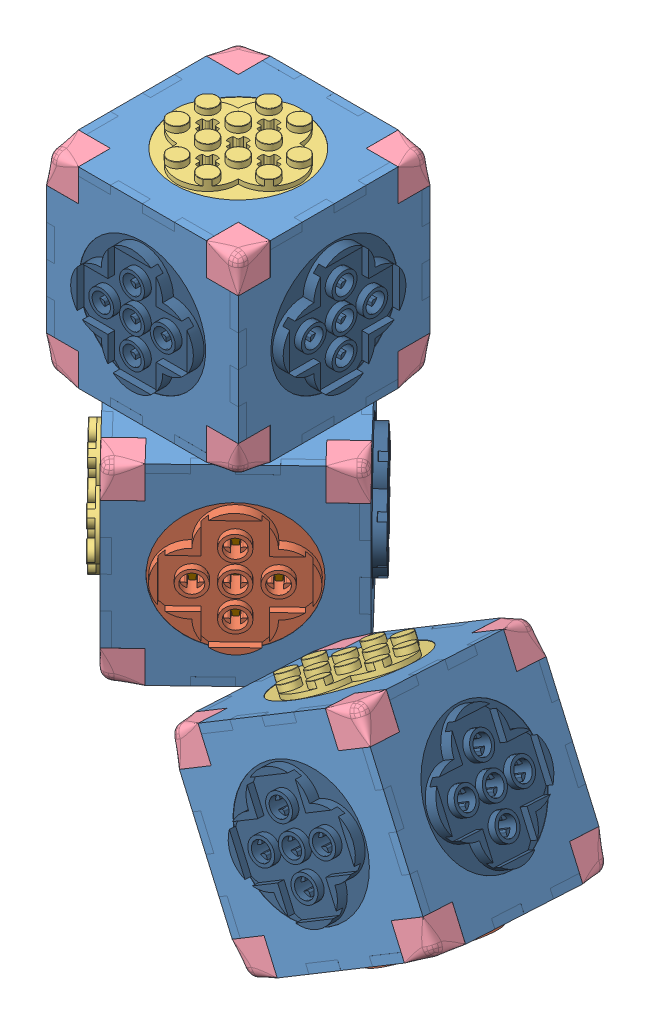
SolidWorks assembly demo, configuration Default. Lengths in mm.
Overall size (276.34 303.89 216.73).
87 component instances, 10 part files, 2 mates.
Components (placement in the parent):
- Assem2.2-1: Assem2.2 [Default] at (21.6339 91.8261 157.3479) size (152.36 197.99 106.71)
  - Partfina1.1-1: Partfina1.1 [Default] at (20.7363 27.7701 41.1813) size (50 50 2.1) (hidden)
  - Partfina1.1-2: Partfina1.1 [Default] at (38.638 27.7701 13.2813) x (0.000056 0 -1) z (1 0 0.000056) size (50 50 2.1) (hidden)
  - Partfina1.1-4: Partfina1.1 [Default] at (10.7387 27.7728 -4.62) x (-1 0.00009 -0.000071) z (0.000071 -0.000198 -1) size (50 50 2.1)
  - Partfina1.1-5: Partfina1.1 [Default] at (-7.1609 27.774 23.278) x (0 0 1) z (-1 0 0) size (50 50 2.1)
  - Partfina1.1-6: Partfina1.1 [Default] at (20.7363 -0.1265 13.2846) x (0 0 -1) z (0 -1 0) size (50 50 2.1)
  - 42_NEGATIVE_TURNok-1: 42_NEGATIVE_TURNok [Default] at (15.7363 -4.9265 26.2846) x (1 0 0.000001) z (-0.000001 0 1) size (117.99 40.06 72.36)
  - Partfina1.1-7: Partfina1.1 [Default] at (10.7391 45.674 23.278) x (-1 0 0) z (0 1 0) size (50 50 2.1)
  - 42_positive-1: 42_positive [Default] at (118.3117 45.674 32.2842) size (63.9 8.98 46.69)
  - 42_positive-2: 42_positive [Default] at (-7.1609 36.7803 -84.2945) x (0 0 -1) z (0 1 0) size (63.9 8.98 46.69)
  - 42_positive-3: 42_positive [Default] at (1.7335 125.3451 -4.64) x (0.000015 1 -0.000198) z (-1 0.000015 -0.000071) size (63.9 8.98 46.69)
  - angle-1: angle [Default] at (-5.0959 39.444 -2.5536) size (10.84 10.84 10.84)
  - angle-2: angle [Default] at (36.5739 39.4401 -2.5505) x (-0.000056 0 1) z (-1 0 -0.000056) size (10.84 10.84 10.84)
  - angle-3: angle [Default] at (36.568 39.4401 39.1163) x (-1 0 0) z (0 0 -1) size (10.84 10.84 10.84)
  - angle-4: angle [Default] at (-5.0959 39.444 39.1097) x (0 0 -1) z (1 0 0) size (10.84 10.84 10.84)
  - angle-5: angle [Default] at (36.568 6.1035 39.1163) x (0 0 -1) z (-1 0 0) size (10.84 10.84 10.84)
  - angle-6: angle [Default] at (36.5739 6.1035 -2.5505) x (-1 0 -0.000056) z (-0.000056 0 1) size (10.84 10.84 10.84)
  - angle-7: angle [Default] at (-5.0951 6.108 -2.5519) x (-0.000071 0.000198 1) z (1 -0.00009 0.000071) size (10.84 10.84 10.84)
  - angle-8: angle [Default] at (-5.0959 6.1074 39.1097) x (1 0 0) z (0 0 -1) size (10.84 10.84 10.84)
  - HS-55_Servo-2: HS-55_Servo [Default] at (15.7363 4.1163 18.2846) x (0.707107 0 -0.707106) z (-0.707106 0 -0.707107) size (32.54 27 11.73)
    - Hi-Tec_HS-55_Body-1: Hi-Tec_HS-55_Body [Default] at origin size (32.54 24.06 11.73)
    - Hi-Tec_HS-55_Shaft-1: Hi-Tec_HS-55_Shaft [Default] at (0 3 0) x (0.999553 0 0.029907) z (-0.029907 0 0.999553) size (3.75 3 3.75)
  - motor_laser adapter-1: motor_laser adapter [Default] at (19.7166 -9.2257 25.7533) x (0.707107 0 -0.707107) z (-0.707107 0 -0.707107) size (56.91 27 56.91)
  - motor_fit-1: motor_fit [Default] at (19.7166 -9.7157 25.7533) x (0.707107 0 -0.707106) z (-0.707106 0 -0.707107) size (32.54 27 22)
  - 42_NEGATIVE_TURN-3: 42_NEGATIVE_TURN [Default] at (15.7363 -1.4265 26.2846) size (115.49 39.26 69.86)
  - 42_NEGATIVE-1: 42_NEGATIVE [Default] at (43.4391 22.774 10.278) x (0 -1 0) z (0 0 -1) size (117.99 40.06 72.36)
  - Partfina1.1-8: Partfina1.1 [Default] at (38.6391 27.774 13.278) x (0 0 -1) z (1 0 0) size (50 50 2.1)
  - Partfina1.1-9: Partfina1.1 [Default] at (20.7391 27.774 41.178) size (50 50 2.1)
  - 42_NEGATIVE-2: 42_NEGATIVE [Default] at (7.7391 22.774 45.978) x (0 1 0) z (-1 0 0) size (117.99 40.06 72.36)
- Assem2.2-2: Assem2.2 [Default] at (39.9561 76.5387 204.7196) x (0 -1 0) z (0.721396 0 -0.692523) size (152.36 197.99 106.71)
  - Partfina1.1-1: Partfina1.1 [Default] at (20.7363 27.7701 41.1813) size (50 50 2.1) (hidden)
  - Partfina1.1-2: Partfina1.1 [Default] at (38.638 27.7701 13.2813) x (0.000056 0 -1) z (1 0 0.000056) size (50 50 2.1) (hidden)
  - Partfina1.1-4: Partfina1.1 [Default] at (10.7387 27.7728 -4.62) x (-1 0.00009 -0.000071) z (0.000071 -0.000198 -1) size (50 50 2.1)
  - Partfina1.1-5: Partfina1.1 [Default] at (-7.1609 27.774 23.278) x (0 0 1) z (-1 0 0) size (50 50 2.1)
  - Partfina1.1-6: Partfina1.1 [Default] at (20.7363 -0.1265 13.2846) x (0 0 -1) z (0 -1 0) size (50 50 2.1)
  - 42_NEGATIVE_TURNok-1: 42_NEGATIVE_TURNok [Default] at (15.7363 -4.9265 26.2846) x (1 0 0.000001) z (-0.000001 0 1) size (117.99 40.06 72.36)
  - Partfina1.1-7: Partfina1.1 [Default] at (10.7391 45.674 23.278) x (-1 0 0) z (0 1 0) size (50 50 2.1)
  - 42_positive-1: 42_positive [Default] at (118.3117 45.674 32.2842) size (63.9 8.98 46.69)
  - 42_positive-2: 42_positive [Default] at (-7.1609 36.7803 -84.2945) x (0 0 -1) z (0 1 0) size (63.9 8.98 46.69)
  - 42_positive-3: 42_positive [Default] at (1.7335 125.3451 -4.64) x (0.000015 1 -0.000198) z (-1 0.000015 -0.000071) size (63.9 8.98 46.69)
  - angle-1: angle [Default] at (-5.0959 39.444 -2.5536) size (10.84 10.84 10.84)
  - angle-2: angle [Default] at (36.5739 39.4401 -2.5505) x (-0.000056 0 1) z (-1 0 -0.000056) size (10.84 10.84 10.84)
  - angle-3: angle [Default] at (36.568 39.4401 39.1163) x (-1 0 0) z (0 0 -1) size (10.84 10.84 10.84)
  - angle-4: angle [Default] at (-5.0959 39.444 39.1097) x (0 0 -1) z (1 0 0) size (10.84 10.84 10.84)
  - angle-5: angle [Default] at (36.568 6.1035 39.1163) x (0 0 -1) z (-1 0 0) size (10.84 10.84 10.84)
  - angle-6: angle [Default] at (36.5739 6.1035 -2.5505) x (-1 0 -0.000056) z (-0.000056 0 1) size (10.84 10.84 10.84)
  - angle-7: angle [Default] at (-5.0951 6.108 -2.5519) x (-0.000071 0.000198 1) z (1 -0.00009 0.000071) size (10.84 10.84 10.84)
  - angle-8: angle [Default] at (-5.0959 6.1074 39.1097) x (1 0 0) z (0 0 -1) size (10.84 10.84 10.84)
  - HS-55_Servo-2: HS-55_Servo [Default] at (15.7363 4.1163 18.2846) x (0.707107 0 -0.707106) z (-0.707106 0 -0.707107) size (32.54 27 11.73)
    - Hi-Tec_HS-55_Body-1: Hi-Tec_HS-55_Body [Default] at origin size (32.54 24.06 11.73)
    - Hi-Tec_HS-55_Shaft-1: Hi-Tec_HS-55_Shaft [Default] at (0 3 0) x (0.999553 0 0.029907) z (-0.029907 0 0.999553) size (3.75 3 3.75)
  - motor_laser adapter-1: motor_laser adapter [Default] at (19.7166 -9.2257 25.7533) x (0.707107 0 -0.707107) z (-0.707107 0 -0.707107) size (56.91 27 56.91)
  - motor_fit-1: motor_fit [Default] at (19.7166 -9.7157 25.7533) x (0.707107 0 -0.707106) z (-0.707106 0 -0.707107) size (32.54 27 22)
  - 42_NEGATIVE_TURN-3: 42_NEGATIVE_TURN [Default] at (15.7363 -1.4265 26.2846) size (115.49 39.26 69.86)
  - 42_NEGATIVE-1: 42_NEGATIVE [Default] at (43.4391 22.774 10.278) x (0 -1 0) z (0 0 -1) size (117.99 40.06 72.36)
  - Partfina1.1-8: Partfina1.1 [Default] at (38.6391 27.774 13.278) x (0 0 -1) z (1 0 0) size (50 50 2.1)
  - Partfina1.1-9: Partfina1.1 [Default] at (20.7391 27.774 41.178) size (50 50 2.1)
  - 42_NEGATIVE-2: 42_NEGATIVE [Default] at (7.7391 22.774 45.978) x (0 1 0) z (-1 0 0) size (117.99 40.06 72.36)
- Assem2.2-3: Assem2.2 [Default] at (104.2409 14.6081 192.6606) x (0.87122 0.475159 -0.123287) z (0.072918 0.123097 0.989712) size (152.36 197.99 106.71)
  - Partfina1.1-1: Partfina1.1 [Default] at (20.7363 27.7701 41.1813) size (50 50 2.1) (hidden)
  - Partfina1.1-2: Partfina1.1 [Default] at (38.638 27.7701 13.2813) x (0.000056 0 -1) z (1 0 0.000056) size (50 50 2.1) (hidden)
  - Partfina1.1-4: Partfina1.1 [Default] at (10.7387 27.7728 -4.62) x (-1 0.00009 -0.000071) z (0.000071 -0.000198 -1) size (50 50 2.1)
  - Partfina1.1-5: Partfina1.1 [Default] at (-7.1609 27.774 23.278) x (0 0 1) z (-1 0 0) size (50 50 2.1)
  - Partfina1.1-6: Partfina1.1 [Default] at (20.7363 -0.1265 13.2846) x (0 0 -1) z (0 -1 0) size (50 50 2.1)
  - 42_NEGATIVE_TURNok-1: 42_NEGATIVE_TURNok [Default] at (15.7363 -4.9265 26.2846) x (1 0 0.000001) z (-0.000001 0 1) size (117.99 40.06 72.36)
  - Partfina1.1-7: Partfina1.1 [Default] at (10.7391 45.674 23.278) x (-1 0 0) z (0 1 0) size (50 50 2.1)
  - 42_positive-1: 42_positive [Default] at (118.3117 45.674 32.2842) size (63.9 8.98 46.69)
  - 42_positive-2: 42_positive [Default] at (-7.1609 36.7803 -84.2945) x (0 0 -1) z (0 1 0) size (63.9 8.98 46.69)
  - 42_positive-3: 42_positive [Default] at (1.7335 125.3451 -4.64) x (0.000015 1 -0.000198) z (-1 0.000015 -0.000071) size (63.9 8.98 46.69)
  - angle-1: angle [Default] at (-5.0959 39.444 -2.5536) size (10.84 10.84 10.84)
  - angle-2: angle [Default] at (36.5739 39.4401 -2.5505) x (-0.000056 0 1) z (-1 0 -0.000056) size (10.84 10.84 10.84)
  - angle-3: angle [Default] at (36.568 39.4401 39.1163) x (-1 0 0) z (0 0 -1) size (10.84 10.84 10.84)
  - angle-4: angle [Default] at (-5.0959 39.444 39.1097) x (0 0 -1) z (1 0 0) size (10.84 10.84 10.84)
  - angle-5: angle [Default] at (36.568 6.1035 39.1163) x (0 0 -1) z (-1 0 0) size (10.84 10.84 10.84)
  - angle-6: angle [Default] at (36.5739 6.1035 -2.5505) x (-1 0 -0.000056) z (-0.000056 0 1) size (10.84 10.84 10.84)
  - angle-7: angle [Default] at (-5.0951 6.108 -2.5519) x (-0.000071 0.000198 1) z (1 -0.00009 0.000071) size (10.84 10.84 10.84)
  - angle-8: angle [Default] at (-5.0959 6.1074 39.1097) x (1 0 0) z (0 0 -1) size (10.84 10.84 10.84)
  - HS-55_Servo-2: HS-55_Servo [Default] at (15.7363 4.1163 18.2846) x (0.707107 0 -0.707106) z (-0.707106 0 -0.707107) size (32.54 27 11.73)
    - Hi-Tec_HS-55_Body-1: Hi-Tec_HS-55_Body [Default] at origin size (32.54 24.06 11.73)
    - Hi-Tec_HS-55_Shaft-1: Hi-Tec_HS-55_Shaft [Default] at (0 3 0) x (0.999553 0 0.029907) z (-0.029907 0 0.999553) size (3.75 3 3.75)
  - motor_laser adapter-1: motor_laser adapter [Default] at (19.7166 -9.2257 25.7533) x (0.707107 0 -0.707107) z (-0.707107 0 -0.707107) size (56.91 27 56.91)
  - motor_fit-1: motor_fit [Default] at (19.7166 -9.7157 25.7533) x (0.707107 0 -0.707106) z (-0.707106 0 -0.707107) size (32.54 27 22)
  - 42_NEGATIVE_TURN-3: 42_NEGATIVE_TURN [Default] at (15.7363 -1.4265 26.2846) size (115.49 39.26 69.86)
  - 42_NEGATIVE-1: 42_NEGATIVE [Default] at (43.4391 22.774 10.278) x (0 -1 0) z (0 0 -1) size (117.99 40.06 72.36)
  - Partfina1.1-8: Partfina1.1 [Default] at (38.6391 27.774 13.278) x (0 0 -1) z (1 0 0) size (50 50 2.1)
  - Partfina1.1-9: Partfina1.1 [Default] at (20.7391 27.774 41.178) size (50 50 2.1)
  - 42_NEGATIVE-2: 42_NEGATIVE [Default] at (7.7391 22.774 45.978) x (0 1 0) z (-1 0 0) size (117.99 40.06 72.36)
Mates (geometry in assembly coordinates):
- Distance1: distance = 4 mm anti-aligned: plane of Assem2.2-1/42_NEGATIVE_TURNok-1 through (37.3702 89.6996 175.6325) normal (0 -1 0); plane of Assem2.2-2/42_positive-2 through (26.0589 85.6996 175.4016) normal (0 1 0)
- Concentric3: concentric anti-aligned: circle of Assem2.2-1/Partfina1.1-6; circle of Assem2.2-2/Partfina1.1-5
